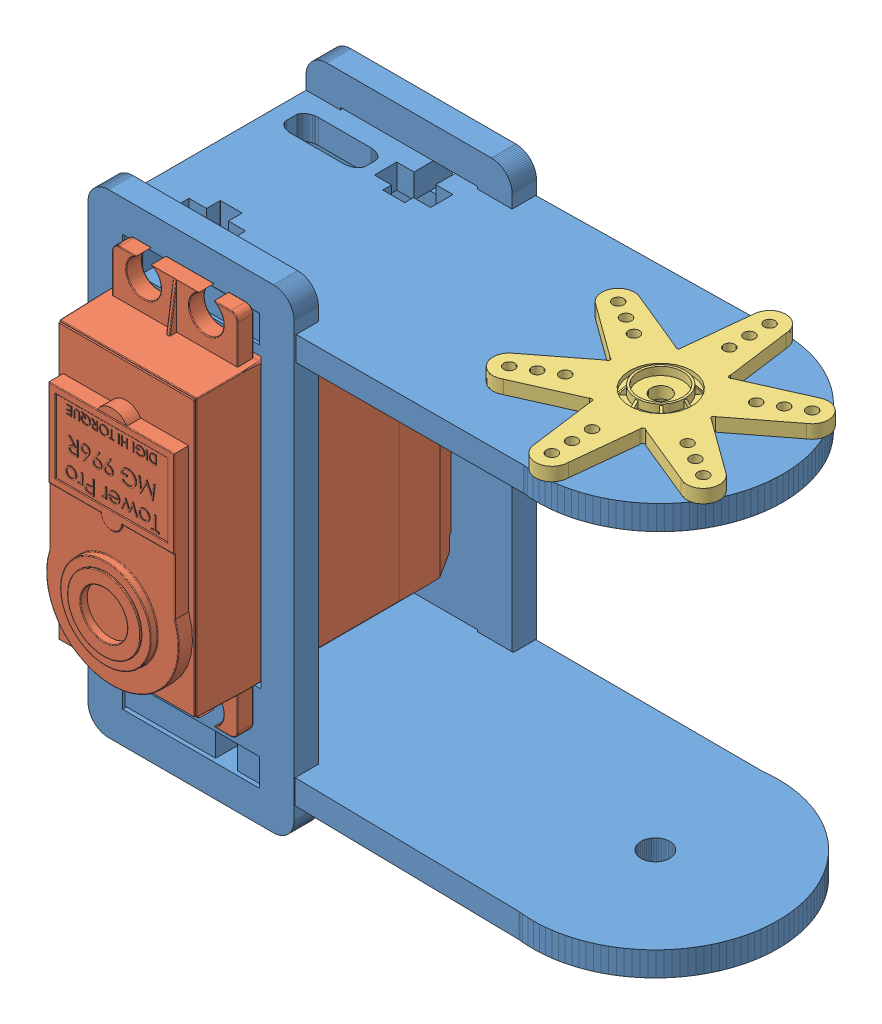
SolidWorks assembly Assem4, configuration Default. Lengths in mm.
Overall size (82.19 68.25 48.82).
4 component instances, 3 part files, 2 mates.
Components (placement in the parent):
- right_hip_pelvis_clamp_100-1: right_hip_pelvis_clamp_100 [Default] at origin size (82.19 68.25 36.02)
- main_assembly-1: main_assembly [Default] at (30.4676 72.9794 -23.8185) x (-0.999998 0 0.001979) z (0.001979 0 0.999998) size (20 53 41.5)
  - main_body-1: main_body [Default] at (15.1003 34.2066 38.7045) size (20 53 41.5)
- servo_arm_6_sided-1: servo_arm_6_sided [Default] at (65.2251 64.5096 17.0687) x (0.014053 0 0.999901) z (-0.999901 0 0.014053) size (36.45 6.25 32.2)
Mates (geometry in assembly coordinates):
- Coincident2: coincident anti-aligned: line of right_hip_pelvis_clamp_100-1 through (5.4835 18.1665 34.9356) axis (0 1 0); line of main_assembly-1/main_body-1 through (5.4835 58.5228 34.9356) axis (0 -1 0)
- ProfileCenter1: profile center aligned: circle of right_hip_pelvis_clamp_100-1; circle of servo_arm_6_sided-1
